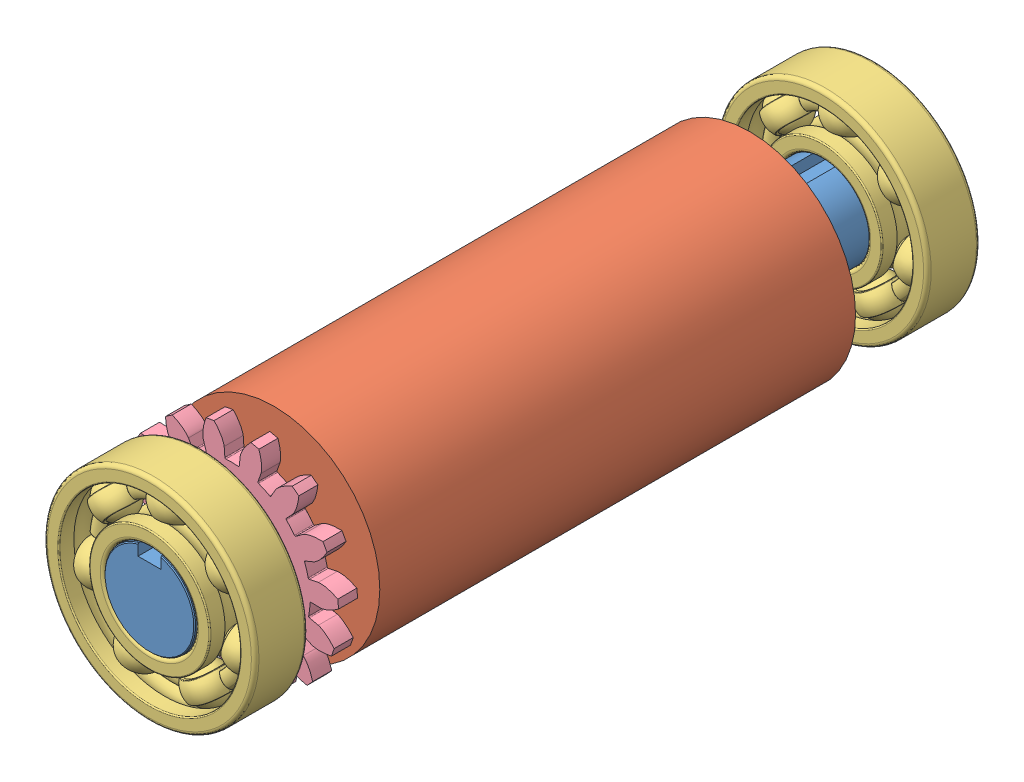
SolidWorks assembly Roller Assembly, configuration Default. Lengths in mm.
Overall size (22.61 22.53 76.2).
5 component instances, 4 part files, 7 mates.
Components (placement in the parent):
- 1497K4 1045 Carbon Steel Keyed Rotary Shaft-1: 1497K4 1045 Carbon Steel Keyed Rotary Shaft [1497K4] at origin size (9.53 9.37 76.2)
- 2029N13 Neoprene Foam Tube-1: 2029N13 Neoprene Foam Tube [Default] x (0 0 -1) z (1 0 0) size (50 22.23 22.23)
- 60355K165 Ball Bearing-1: 60355K165 Ball Bearing [60355K165] at (0 0 35.3219) size (22.23 22.23 5.56)
- 60355K165 Ball Bearing-2: 60355K165 Ball Bearing [60355K165] at (0 0 -35.3219) size (22.23 22.23 5.56)
- Sweeper Gear-2: Sweeper Gear [Default] at (0 0 28.5399) x (0 0 -1) z (1 0 0) size (2 22.53 22.61)
Mates (geometry in assembly coordinates):
- Concentric1: concentric anti-aligned: cylinder of 1497K4 1045 Carbon Steel Keyed Rotary Shaft-1 through (0 0 38.1) axis (0 0 -1) radius 4.7625; cylinder of 2029N13 Neoprene Foam Tube-1 through (0 0 -25) axis (0 0 1) radius 4.7625
- Width1: width anti-aligned: plane of 2029N13 Neoprene Foam Tube-1 through (0 0 -25) normal (0 0 -1); plane of 2029N13 Neoprene Foam Tube-1 through (0 0 25) normal (0 0 1); plane of 1497K4 1045 Carbon Steel Keyed Rotary Shaft-1 through (0 0 38.1) normal (0 0 1); plane of 1497K4 1045 Carbon Steel Keyed Rotary Shaft-1 through (0 0 -38.1) normal (0 0 -1)
- Concentric2: concentric anti-aligned: cylinder of 1497K4 1045 Carbon Steel Keyed Rotary Shaft-1 through (0 0 38.1) axis (0 0 -1) radius 4.7625; cylinder of 60355K165 Ball Bearing-1 through (0 0 38.1) axis (0 0 1) radius 4.7625
- Coincident1: coincident aligned: plane of 1497K4 1045 Carbon Steel Keyed Rotary Shaft-1 through (0 0 38.1) normal (0 0 1); plane of 60355K165 Ball Bearing-1 through (0 5.1613 38.1) normal (0 0 1)
- Concentric3: concentric anti-aligned: cylinder of 1497K4 1045 Carbon Steel Keyed Rotary Shaft-1 through (0 0 38.1) axis (0 0 -1) radius 4.7625; cylinder of 60355K165 Ball Bearing-2 through (0 0 -32.5438) axis (0 0 1) radius 4.7625
- Coincident2: coincident aligned: plane of 1497K4 1045 Carbon Steel Keyed Rotary Shaft-1 through (0 0 -38.1) normal (0 0 -1); plane of 60355K165 Ball Bearing-2 through (0 5.1613 -38.1) normal (0 0 -1)
- Concentric5: concentric aligned: cylinder of 1497K4 1045 Carbon Steel Keyed Rotary Shaft-1 through (0 0 38.1) axis (0 0 -1) radius 4.7625; cylinder of Sweeper Gear-2 through (0 0 29.5399) axis (0 0 -1) radius 4.77
